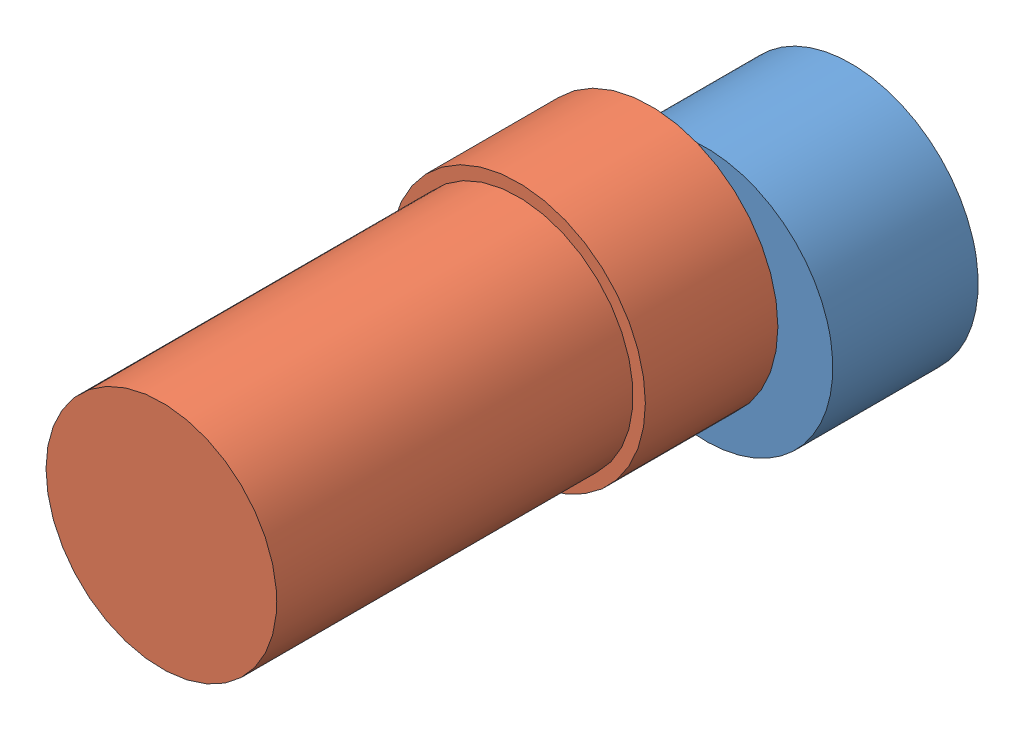
SolidWorks assembly Drive Wheel Rough Assembly, configuration Default. Lengths in mm.
Overall size (42.18 47.38 94.88).
2 component instances, 2 part files, 6 mates.
Components (placement in the parent):
- Wheel - rough-1: Wheel - rough [Default] at (0 17.5 -45.8572) x (0.972576 0.232587 0) z (0 0 1) size (35 35 20)
- Motor Barber Coleman geared-1: Motor Barber Coleman geared [Default] at (0 26.2186 0) x (0 0 1) z (-1 0 0) size (89.87 35.14 35.14)
Mates (geometry in assembly coordinates):
- Parallel1: parallel aligned: plane of Wheel - rough-1; plane of Motor Barber Coleman geared-1 through (5.5361 20.5607 -25.8572) normal (-0.232587 0.972576 0)
- Concentric1: concentric anti-aligned: cylinder of Wheel - rough-1 through (0 17.5 -25.8572) axis (0 0 -1) radius 4; cylinder of Motor Barber Coleman geared-1 through (0 17.5 -40.8432) axis (0 0 1) radius 2.3749
- Coincident5: coincident: plane of Wheel - rough-1 through (0 17.5 -25.8572) normal (0 0 1); point of Motor Barber Coleman geared-1
- Tangent2: tangent anti-aligned: cylinder of Wheel - rough-1 through (0 17.5 -25.8572) axis (0 0 -1) radius 17.5; plane of assembly through (0 0 0) normal (0 1 0)
- Coincident6: coincident anti-aligned: plane of Motor Barber Coleman geared-1 through (0 26.2186 0) normal (-1 0 0); plane of assembly through (0 0 0) normal (1 0 0)
- Coincident8: coincident aligned: plane of Motor Barber Coleman geared-1 through (0 26.2186 0) normal (0 0 1); plane of assembly through (0 0 0) normal (0 0 1)
